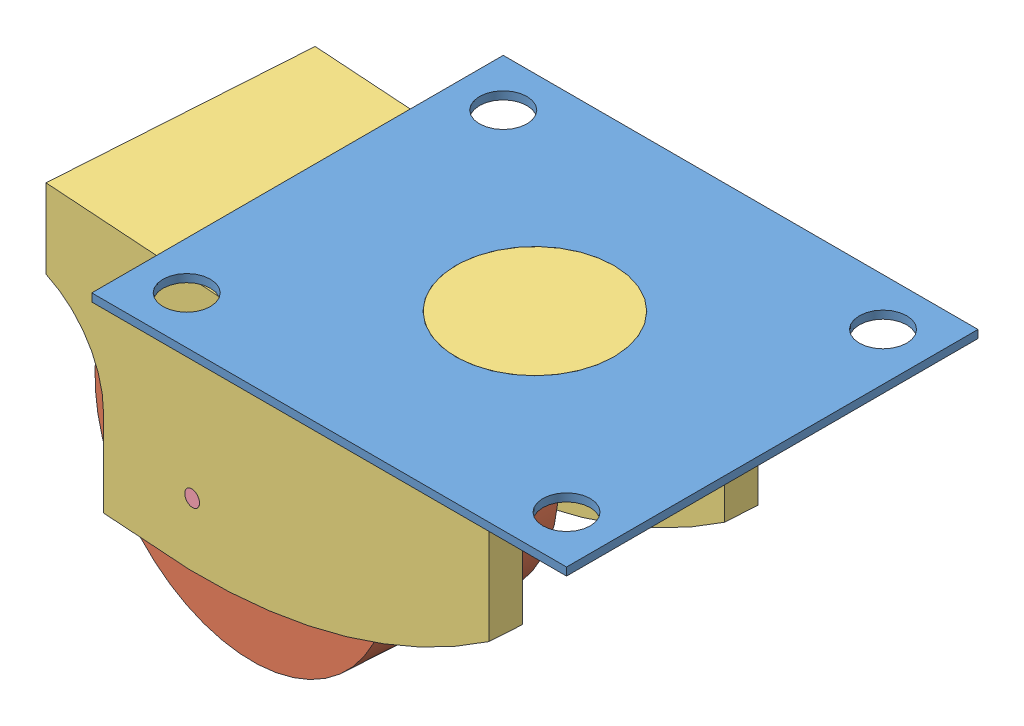
SolidWorks assembly assembly, configuration Default. Lengths in mm.
Overall size (52.65 33.09 33.02).
5 component instances, 4 part files, 8 mates.
Components (placement in the parent):
- top_plate-1: top_plate [Default] at (42.3339 22.3352 36.5646) size (38.1 0.64 33.02)
- wheel-1: wheel [Default] at (5.8252 5.1902 12.5531) x (-0.970502 0.232645 -0.063259) z (-0.065044 0 0.997882) size (25.4 25.4 13.97)
- connector3-1: connector3 [Default] at (30.2269 20.4302 30.6887) x (0.065044 0 -0.997882) z (0.997882 0 0.065044) size (20.32 22.86 38.1)
- wheel_screw-1: wheel_screw [Default] at (5.0296 4.9587 24.5919) x (0.996789 -0.046802 0.064973) z (-0.065044 0 0.997882) size (1.27 1.27 4.45)
- wheel_screw-3: wheel_screw [Default] at (5.7839 4.9584 13.1868) x (-0.997882 0 -0.065044) z (0.065044 0 -0.997882) size (1.27 1.27 4.45)
Mates (geometry in assembly coordinates):
- Concentric1: concentric anti-aligned: cylinder of top_plate-1 through (23.2839 22.3352 20.0546) axis (0 1 0) radius 6.35; cylinder of connector3-1 through (23.2839 22.9702 20.0546) axis (0 -1 0) radius 6.35
- Coincident4: coincident aligned: plane of top_plate-1 through (42.3339 22.9702 36.5646) normal (0 1 0); plane of connector3-1 through (23.2839 22.9702 20.0546) normal (0 1 0)
- Coincident5: coincident anti-aligned: plane of wheel-1 through (5.0404 5.1902 24.5926) normal (-0.065044 0 0.997882); plane of wheel_screw-1 through (5.0404 5.1902 24.5926) normal (0.065044 0 -0.997882)
- Concentric2: concentric anti-aligned: cylinder of wheel-1 through (5.0404 5.1902 24.5926) axis (-0.065044 0 0.997882) radius 0.635; cylinder of wheel_screw-1 through (4.7513 5.1902 29.0282) axis (0.065044 0 -0.997882) radius 0.635
- Concentric5: concentric anti-aligned: cylinder of wheel-1 through (5.7839 5.1902 13.1868) axis (0.065044 0 -0.997882) radius 0.635; cylinder of wheel_screw-3 through (6.073 5.1902 8.7512) axis (-0.065044 0 0.997882) radius 0.635
- Coincident9: coincident anti-aligned: plane of wheel-1 through (5.7839 5.1902 13.1868) normal (0.065044 0 -0.997882); plane of wheel_screw-3 through (5.7839 5.1902 13.1868) normal (-0.065044 0 0.997882)
- Concentric6: concentric aligned: cylinder of connector3-1 through (4.7513 5.1902 29.0282) axis (0.065044 0 -0.997882) radius 0.635; cylinder of wheel_screw-1 through (4.7513 5.1902 29.0282) axis (0.065044 0 -0.997882) radius 0.635
- Coincident10: coincident aligned: circle of connector3-1; plane of wheel_screw-3 through (6.073 5.1902 8.7512) normal (0.065044 0 -0.997882)
